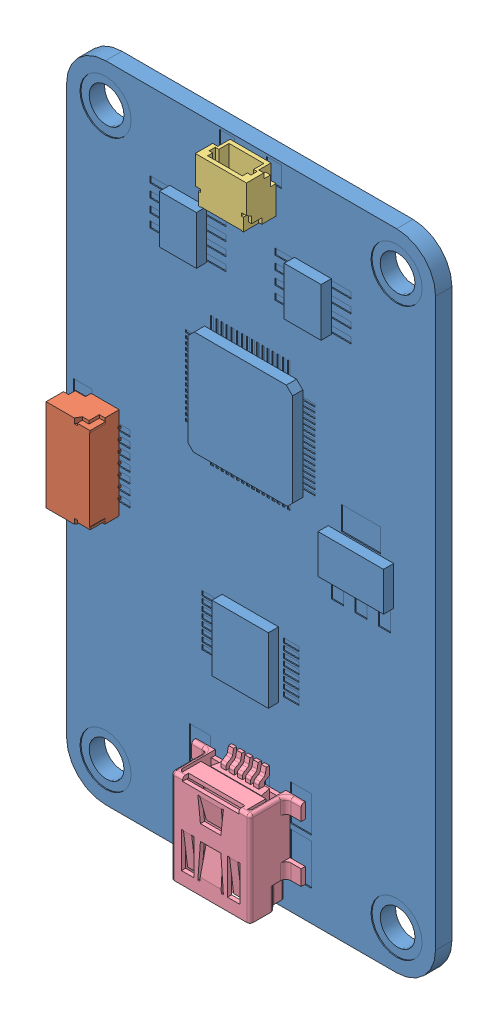
SolidWorks assembly USB2CAN, configuration Default. Lengths in mm.
Overall size (36.07 62.99 5.5).
4 component instances, 4 part files, 9 mates.
Components (placement in the parent):
- USB2CAN_Board-2: USB2CAN_Board [Default] at origin size (36.07 62.99 2.6)
- JST 7-1: JST 7 [Default] at (5.1467 29.619 2.2) x (0 -1 0) z (0 0 -1) size (9 4.32 3.6)
- JST 3-1: JST 3 [Default] at (17.9832 58.1745 2.2) x (-1 0 0) z (0 0 -1) size (5 4.32 3.6)
- Mini USB-1: Mini USB [Default] at (17.9833 5.437 0) x (0 1 0) z (0 0 1) size (10.5 10.7 3.9)
Mates (geometry in assembly coordinates):
- Distance1: distance = 1 mm: line of assembly; plane of assembly; line of JST 7-1 through (5.2167 26.719 0.1) axis (0 0 -1); plane of USB2CAN_Board-2 through (6.2167 26.919 -0.1) normal (-1 0 0)
- Coincident2: coincident: plane of assembly; plane of assembly; plane of USB2CAN_Board-2 through (3.81 59.182 0) normal (0 0 1); plane of JST 7-1 through (5.1467 34.119 0) normal (0 0 -1)
- Distance2: distance = 0.2 mm: plane of assembly; plane of assembly; plane of JST 7-1 through (4.5967 26.519 -0.7) normal (0 -1 0); plane of USB2CAN_Board-2 through (4.6667 26.319 -0.1) normal (0 1 0)
- Coincident4: coincident: plane of assembly; plane of assembly; plane of USB2CAN_Board-2 through (3.81 59.182 0) normal (0 0 1); plane of JST 3-1 through (20.4832 62.4245 0) normal (0 0 -1)
- Distance3: distance = 1 mm: plane of assembly; plane of assembly; plane of JST 3-1 through (17.0832 58.1045 0.1) normal (0 -1 0); plane of USB2CAN_Board-2 through (16.6832 57.1045 -0.1) normal (0 1 0)
- Distance4: distance = 0.2 mm: plane of assembly; plane of assembly; plane of JST 3-1 through (16.8832 58.7245 -0.7) normal (-1 0 0); plane of USB2CAN_Board-2 through (16.6832 58.6545 -0.1) normal (1 0 0)
- Coincident7: coincident: plane of assembly; plane of assembly; plane of USB2CAN_Board-2 through (3.81 59.182 0) normal (0 0 1); plane of Mini USB-1 through (19.3333 11.337 0) normal (0 0 -1)
- Coincident8: coincident: plane of assembly; plane of assembly; plane of USB2CAN_Board-2 through (19.8333 10.337 -0.1) normal (-1 0 0); plane of Mini USB-1 through (19.8333 11.337 1.3) normal (1 0 0)
- Distance5: distance = 1 mm: plane of assembly; plane of assembly; plane of Mini USB-1 through (17.9833 11.337 0) normal (0 1 0); plane of USB2CAN_Board-2 through (19.3333 10.337 -0.1) normal (0 -1 0)
